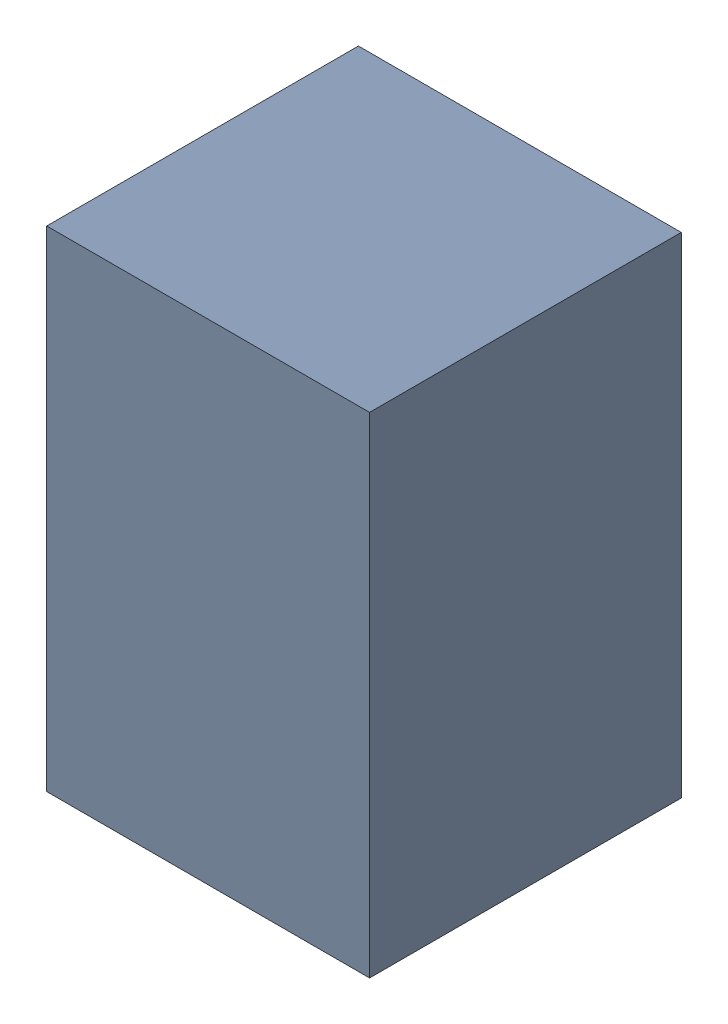
SolidWorks assembly D1-2, configuration Default. Lengths in mm.
Overall size (1.45 2.2 1.4).
2 component instances, 1 part files, 0 mates.
Components (placement in the parent):
- 959209888-2-1: 959209888-2 [Default] at (77.089 89.876 0) size (1.45 2.2 1.4)
  - Extruded-91-1: Extruded-91 [Default] at origin size (1.45 2.2 1.4)
